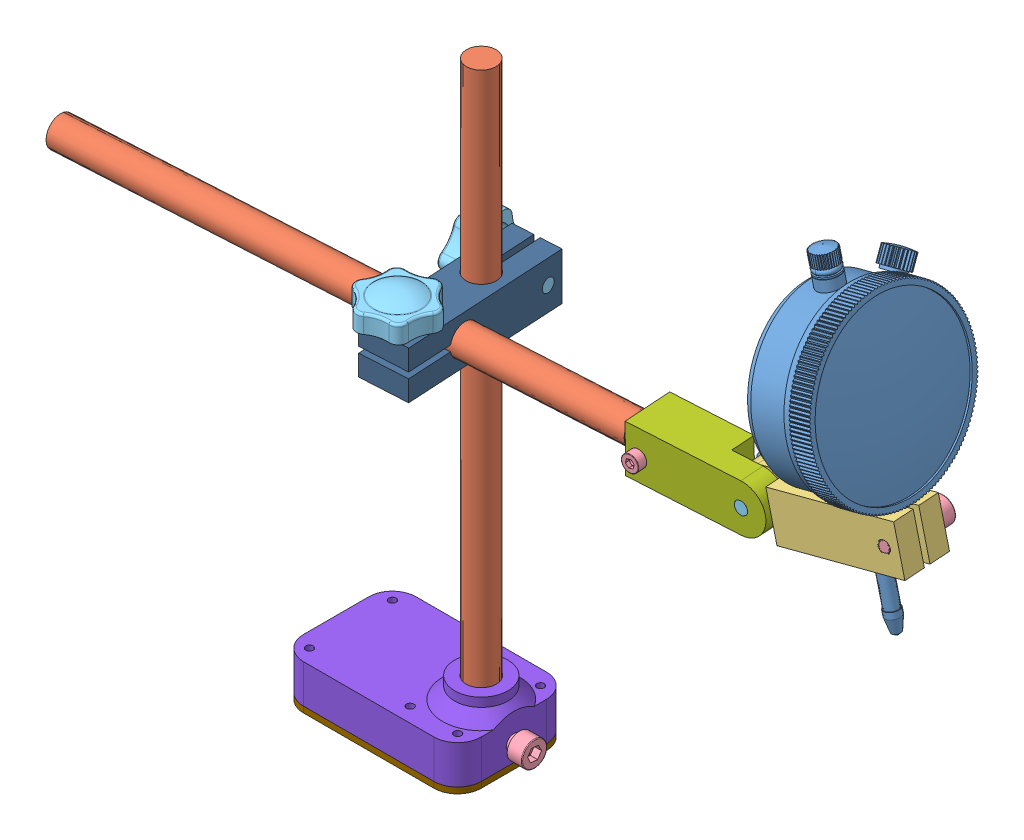
SolidWorks assembly MagneticIndicatorStand, configuration Default. Lengths in mm.
Overall size (285.67 218.5 77.32).
21 component instances, 11 part files, 37 mates.
Components (placement in the parent):
- Dial Indicator-1: Dial Indicator [1..10 mm] at (123.6279 173.3234 8.3001) x (-0.05089 0.00969 -0.998657) z (0.216392 -0.976091 -0.020498) size (60.42 25.7 106.32)
- SteelRod-2: SteelRod [Custom part] at (-120.3983 129.9424 21.8755) x (0.056811 -0.008371 0.99835) z (0.000476 0.999965 0.008357) size (10 200 10)
- SteelRod-3: SteelRod [Custom part] at (0 200.5087 0) x (1 0 0) z (0 0 -1) size (10 200 10)
- IndicatorHolder-1: IndicatorHolder [Custom Part] at (96.5053 128.2048 9.5181) x (-0.056811 0.008371 -0.99835) z (0.974652 0.2172 -0.053641) size (16 16 60)
- socket head cap screw_iso-1: socket head cap screw_iso [ISO 4762 M5 x 16 - 16N] at (149.3727 140.2596 -6.4107) x (0.056811 -0.008371 0.99835) z (-0.74666 0.663468 0.048051) size (21 8.5 8.5)
- socket head cap screw_iso-2: socket head cap screw_iso [ISO 4762 M3 x 6 - 6N] at (73.0359 129.842 22.8872) x (-0.056811 0.008371 -0.99835) z (-0.69019 -0.722865 0.033214) size (9 5.5 5.5)
- ClampingScrewKnob-1: ClampingScrewKnob [M5x16] at (103.848 130.0094 1.1022) x (-0.793441 -0.607327 0.040058) z (-0.056811 0.008371 -0.99835) size (21.59 24 27.35)
- ClampingScrewKnob-2: ClampingScrewKnob [M5x16] at (-8.8393 129.9424 -14.5213) x (-0.045305 -0.603378 -0.796167) z (-0.998385 0 0.056813) size (21.59 24 27.35)
- ClampingScrewKnob-3: ClampingScrewKnob [M5x16] at (1.7044 137.9424 29.9515) x (0.690195 0 -0.723623) z (0 1 0) size (21.59 24 27.35)
- socket head cap screw_iso-5: socket head cap screw_iso [ISO 4762 M5 x 10 - 10N] at (18 6 0) x (-1 0 0) z (0 -0.56518 -0.824967) size (15 8.5 8.5)
- socket countersunk head screw_iso-1: socket countersunk head screw_iso [ISO 10642 - M3 x 10 - 10N] at (6 -2.11 -14) x (0 1 0) z (-0.357031 0 0.934092) size (10 5.54 5.54)
- socket countersunk head screw_iso-2: socket countersunk head screw_iso [ISO 10642 - M3 x 10 - 10N] at (-44 -2.11 -14) x (0 1 0) z (0.821483 0 0.570233) size (10 5.54 5.54)
- socket countersunk head screw_iso-5: socket countersunk head screw_iso [ISO 10642 - M3 x 10 - 10N] at (-10 -2.11 -14) x (0 1 0) z (-0.87933 0 -0.476213) size (10 5.54 5.54)
- socket countersunk head screw_iso-6: socket countersunk head screw_iso [ISO 10642 - M3 x 10 - 10N] at (-44 -2.11 14) x (0 1 0) z (-0.75557 0 0.655068) size (10 5.54 5.54)
- socket countersunk head screw_iso-7: socket countersunk head screw_iso [ISO 10642 - M3 x 10 - 10N] at (-10 -2.11 14) x (0 1 0) z (-0.857294 0 0.514827) size (10 5.54 5.54)
- socket countersunk head screw_iso-8: socket countersunk head screw_iso [ISO 10642 - M3 x 10 - 10N] at (6 -2.11 14) x (0 1 0) z (-0.774019 0 0.633163) size (10 5.54 5.54)
- SecondPartOfIndicatorJoint-1: SecondPartOfIndicatorJoint [Custom Part] at (112.2896 129.9424 8.6345) x (0.056811 -0.008371 0.99835) z (-0.998385 0 0.056813) size (16 16 45)
- BasePart-1: BasePart [Custom Casting Aluminum Part] at origin size (60 20 38)
- Lid-1: Lid [Custom Part] at (-19 0 0) x (1 0 0) z (0 0 -1) size (60 2 38)
- MainJoint-1: MainJoint [Custom Part] at (1.9884 129.9424 34.9435) x (-0.998385 0 0.056813) z (-0.056813 0 -0.998385) size (16 16 55)
- Neodymium Magnet Square-1: Neodymium Magnet Square [25x25x8 - 35 kg] at (-27 1 0) size (25 8 25)
Mates (geometry in assembly coordinates):
- Concentric1: concentric anti-aligned: circle of Dial Indicator-1; cylinder of Part4^MagneticIndicatorStand-1 through (142.0958 130.1701 6.9403) axis (-0.216392 0.976091 0.020498) radius 4.05
- Concentric2: concentric aligned: cylinder of Part4^MagneticIndicatorStand-1 through (150.5657 140.0838 14.5557) axis (-0.056811 0.008371 -0.99835) radius 2.05; cylinder of socket head cap screw_iso-1 through (147.5689 140.5254 -38.1083) axis (-0.056811 0.008371 -0.99835) radius 2.5
- Coincident1: coincident anti-aligned: plane of Part4^MagneticIndicatorStand-1 through (156.2611 133.495 -1.8511) normal (-0.056811 0.008371 -0.99835); plane of socket head cap screw_iso-1 through (152.4735 143.3974 -1.5526) normal (0.056811 -0.008371 0.99835)
- Concentric3: concentric aligned: cylinder of SteelRod-2 through (79.2786 129.9424 10.513) axis (-0.998385 0 0.056813) radius 5; cylinder of Part1^MagneticIndicatorStand-1 through (67.3623 129.9424 11.191) axis (-0.998385 0 0.056813) radius 5.1
- Coincident2: coincident anti-aligned: plane of SteelRod-2 through (79.2786 129.9424 10.513) normal (0.998385 0 -0.056813); circle of Part1^MagneticIndicatorStand-1
- Concentric4: concentric anti-aligned: cylinder of Part4^MagneticIndicatorStand-1 through (104.757 129.8755 17.0758) axis (-0.056811 0.008371 -0.99835) radius 2.55; cylinder of Part1^MagneticIndicatorStand-1 through (104.757 129.8755 17.0758) axis (0.056811 -0.008371 0.99835) radius 2.1
- Coincident3: coincident anti-aligned: plane of Part4^MagneticIndicatorStand-1 through (96.5053 128.2048 9.5181) normal (0.056811 -0.008371 0.99835); plane of Part1^MagneticIndicatorStand-1 through (112.2896 129.9424 8.6345) normal (-0.056811 0.008371 -0.99835)
- Coincident4: coincident anti-aligned: plane of Part4^MagneticIndicatorStand-1 through (156.2611 133.495 -1.8511) normal (-0.056811 0.008371 -0.99835); plane of ClampingScrewKnob-1 through (103.848 130.0094 1.1022) normal (0.056811 -0.008371 0.99835)
- Concentric5: concentric aligned: cylinder of Part4^MagneticIndicatorStand-1 through (104.757 129.8755 17.0758) axis (-0.056811 0.008371 -0.99835) radius 2.55; cylinder of ClampingScrewKnob-1 through (104.757 129.8755 17.0758) axis (-0.056811 0.008371 -0.99835) radius 2.5
- Distance1: distance = 1 mm: point of Dial Indicator-1; plane of Part4^MagneticIndicatorStand-1 through (152.7988 149.1125 -1.5232) normal (-0.216392 0.976091 0.020498)
- Concentric6: concentric aligned: cylinder of Part1^MagneticIndicatorStand-1 through (72.8087 129.8755 18.8938) axis (0.056811 -0.008371 0.99835) radius 1.25; cylinder of socket head cap screw_iso-2 through (74.8397 129.5762 54.5848) axis (0.056811 -0.008371 0.99835) radius 1.5
- Coincident7: coincident anti-aligned: plane of SteelRod-2 through (80.5798 124.9175 13.4017) normal (0.056811 -0.008371 0.99835); plane of socket head cap screw_iso-2 through (73.4044 129.0747 13.8449) normal (-0.056811 0.008371 -0.99835)
- Concentric7: concentric aligned: cylinder of SteelRod-3 through (0 0.5087 0) axis (0 1 0) radius 5; cylinder of Base-1 through (0 20 0) axis (0 1 0) radius 5.1
- Concentric15: concentric aligned: cylinder of Base-1 through (11 6 0) axis (1 0 0) radius 2.1; cylinder of socket head cap screw_iso-5 through (49.75 6 0) axis (1 0 0) radius 2.5
- Coincident19: coincident anti-aligned: plane of SteelRod-3 through (3 -0.6262 5) normal (1 0 0); plane of socket head cap screw_iso-5 through (3 7.6953 -1.1614) normal (-1 0 0)
- Concentric23: concentric aligned: cylinder of Base-1 through (6 0 -14) axis (0 -1 0) radius 1.25; cylinder of socket countersunk head screw_iso-1 through (6 -2.11 -14) axis (0 -1 0) radius 1.5
- Concentric25: concentric aligned: cylinder of Base-1 through (-44 0 -14) axis (0 -1 0) radius 1.25; cylinder of socket countersunk head screw_iso-2 through (-44 -2.11 -14) axis (0 -1 0) radius 1.5
- Coincident31: coincident anti-aligned: plane of Base-1 through (0 0 0) normal (0 -1 0); plane of Lid-1 through (3 0 11) normal (0 1 0)
- Concentric26: concentric aligned: cylinder of Base-1 through (6 0 -14) axis (0 -1 0) radius 1.25; cylinder of Lid-1 through (6 -2 -14) axis (0 -1 0) radius 1.55
- Concentric28: concentric aligned: cylinder of socket countersunk head screw_iso-8 through (6 -2.11 14) axis (0 -1 0) radius 1.5; cylinder of Lid-1 through (6 -2 14) axis (0 -1 0) radius 1.55
- Coincident33: coincident aligned: cone of socket countersunk head screw_iso-8 through (6 -1.52 14) axis (0 1 0); cone of Lid-1 through (6 -2 14) axis (0 1 0)
- Concentric30: concentric aligned: cylinder of socket countersunk head screw_iso-1 through (6 -2.11 -14) axis (0 -1 0) radius 1.5; cylinder of Lid-1 through (6 -2 -14) axis (0 -1 0) radius 1.55
- Coincident34: coincident aligned: cone of socket countersunk head screw_iso-1 through (6 -1.52 -14) axis (0 1 0); cone of Lid-1 through (6 -2 -14) axis (0 1 0)
- Concentric31: concentric aligned: cylinder of socket countersunk head screw_iso-7 through (-10 -2.11 14) axis (0 -1 0) radius 1.5; cylinder of Lid-1 through (-10 -2 14) axis (0 -1 0) radius 1.55
- Coincident35: coincident aligned: cone of socket countersunk head screw_iso-7 through (-10 -1.52 14) axis (0 1 0); cone of Lid-1 through (-10 -2 14) axis (0 1 0)
- Concentric32: concentric aligned: cylinder of socket countersunk head screw_iso-6 through (-44 -2.11 14) axis (0 -1 0) radius 1.5; cylinder of Lid-1 through (-44 -2 14) axis (0 -1 0) radius 1.55
- Coincident36: coincident aligned: cone of socket countersunk head screw_iso-6 through (-44 -1.52 14) axis (0 1 0); cone of Lid-1 through (-44 -2 14) axis (0 1 0)
- Concentric33: concentric aligned: cylinder of socket countersunk head screw_iso-5 through (-10 -2.11 -14) axis (0 -1 0) radius 1.5; cylinder of Lid-1 through (-10 -2 -14) axis (0 -1 0) radius 1.55
- Coincident37: coincident aligned: cone of socket countersunk head screw_iso-5 through (-10 -1.52 -14) axis (0 1 0); cone of Lid-1 through (-10 -2 -14) axis (0 1 0)
- Concentric35: concentric aligned: cylinder of SteelRod-3 through (0 0.5087 0) axis (0 1 0) radius 5; cylinder of Part6-1 through (0 137.9424 0) axis (0 1 0) radius 5.1
- Concentric36: concentric aligned: cylinder of ClampingScrewKnob-2 through (7.1349 129.9424 -15.4303) axis (-0.998385 0 0.056813) radius 2.5; cylinder of Part6-1 through (-8.8393 129.9424 -14.5213) axis (-0.998385 0 0.056813) radius 2.55
- Coincident39: coincident anti-aligned: plane of ClampingScrewKnob-2 through (-8.8393 129.9424 -14.5213) normal (0.998385 0 -0.056813); plane of Part6-1 through (-9.1233 121.9424 -19.5132) normal (-0.998385 0 0.056813)
- Concentric37: concentric anti-aligned: cylinder of SteelRod-2 through (79.2786 129.9424 10.513) axis (-0.998385 0 0.056813) radius 5; cylinder of Part6-1 through (8.8393 129.9424 14.5213) axis (0.998385 0 -0.056813) radius 5.1
- Concentric38: concentric aligned: cylinder of ClampingScrewKnob-3 through (1.7044 121.9424 29.9515) axis (0 1 0) radius 2.5; cylinder of Part6-1 through (1.7044 137.9424 29.9515) axis (0 1 0) radius 2.55
- Coincident40: coincident anti-aligned: plane of ClampingScrewKnob-3 through (1.7044 137.9424 29.9515) normal (0 -1 0); plane of Part6-1 through (-9.1233 137.9424 -19.5132) normal (0 1 0)
- ProfileCenter2: profile center anti-aligned: plane of Base-1 through (0 9 0) normal (0 -1 0); plane of Neodymium Magnet Square-1 through (-27 9 0) normal (0 1 0)
- Concentric40: concentric aligned: cylinder of socket countersunk head screw_iso-5 through (-10 -2.11 -14) axis (0 -1 0) radius 1.5; cylinder of Base-1 through (-10 0 -14) axis (0 -1 0) radius 1.25
